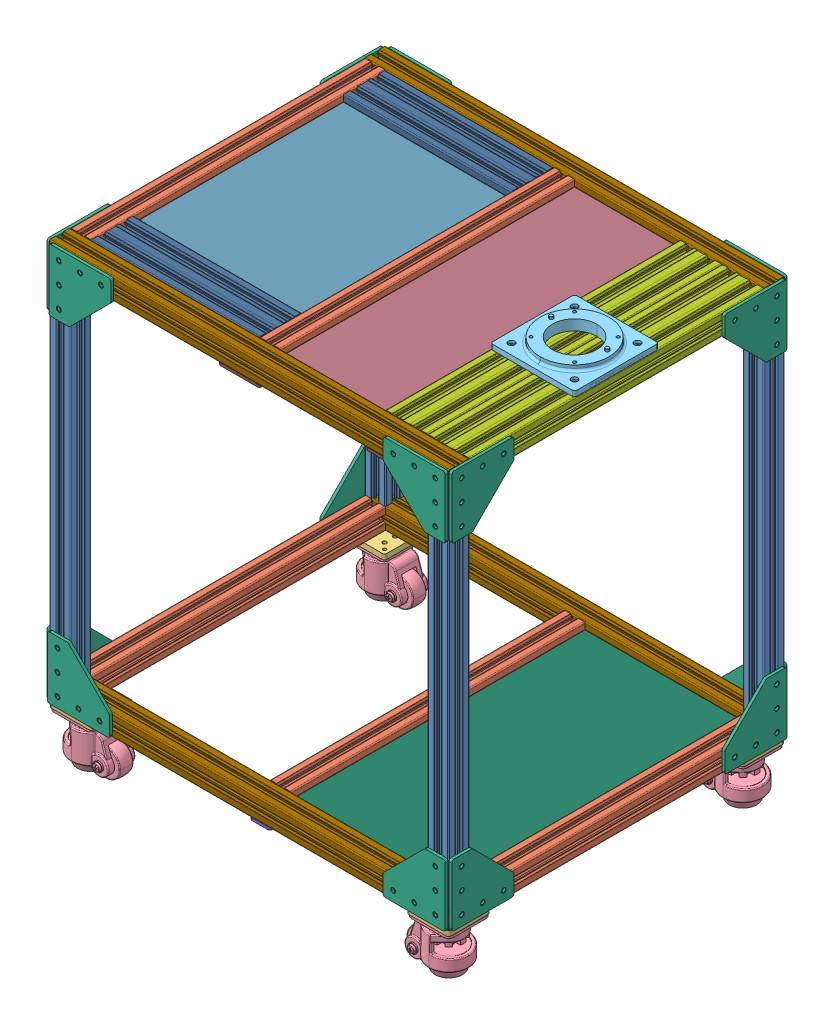
SolidWorks assembly VentionAssembly_13996_v2.7, configuration Default. Lengths in mm.
Overall size (881.9 998.23 752.82).
54 component instances, 15 part files, 4 mates.
Components (placement in the parent):
- VentionAssembly_13996_v2.7.STEP-1: VentionAssembly_13996_v2.7.STEP [Default] at origin size (881.9 998.23 752.82)
  - ST-EXT-001-0765.STEP-1: ST-EXT-001-0765.STEP [Default] at (-347.2932 -765 -630.5247) x (-1 0 0) z (0 1 0) size (45 45 765)
  - ST-EXT-001-0765.STEP-2: ST-EXT-001-0765.STEP [Default] at (-1157.2932 0 -630.5247) x (0 0 -1) z (0 -1 0) size (45 45 765)
  - ST-EXT-001-0765.STEP-3: ST-EXT-001-0765.STEP [Default] at (-1157.2932 0 44.4753) x (0 0 -1) z (0 -1 0) size (45 45 765)
  - ST-EXT-001-0630.STEP-1: ST-EXT-001-0630.STEP [Default] at (-1157.2932 -787.5 21.9753) x (0 -1 0) z (0 0 -1) size (45 45 630)
  - ST-SP-010-0002.STEP-1: ST-SP-010-0002.STEP [Default] at (-1134.7932 -821.25 21.9753) x (0 0 -1) z (1 0 0) size (90 11.25 90)
  - ST-SP-010-0002.STEP-2: ST-SP-010-0002.STEP [Default] at (-1136.7932 -821.25 -608.0247) x (0 0 -1) z (1 0 0) size (90 11.25 90)
  - ST-SP-010-0002.STEP-3: ST-SP-010-0002.STEP [Default] at (-369.7932 -821.25 21.9753) x (0 0 1) z (-1 0 0) size (90 11.25 90)
  - ST-SP-010-0002.STEP-4: ST-SP-010-0002.STEP [Default] at (-369.7932 -821.25 -608.0247) x (0 0 1) z (-1 0 0) size (90 11.25 90)
  - MO-WL-003-0002.STEP-1: MO-WL-003-0002.STEP [Default] at (-1089.2932 -821.25 21.9753) x (0 0 -1) z (1 0 0) size (106.41 104.48 134.91)
  - MO-WL-003-0002.STEP-2: MO-WL-003-0002.STEP [Default] at (-415.2932 -821.25 21.9753) x (0 0 1) z (-1 0 0) size (106.41 104.48 134.91)
  - MO-WL-003-0002.STEP-3: MO-WL-003-0002.STEP [Default] at (-1091.2932 -821.25 -608.0247) x (0 0 -1) z (1 0 0) size (106.41 104.48 134.91)
  - MO-WL-003-0002.STEP-4: MO-WL-003-0002.STEP [Default] at (-415.2932 -821.25 -608.0247) x (0 0 1) z (-1 0 0) size (106.41 104.48 134.91)
  - ST-RB-001-0002.STEP-1: ST-RB-001-0002.STEP [Default] at (-414.7932 45 -293.0247) x (-1 0 0) z (0 0 -1) size (180 27.5 180)
  - ST-EXT-001-0630.STEP-2: ST-EXT-001-0630.STEP [Default] at (-347.2932 -787.5 -608.0247) x (0 -1 0) z (0 0 1) size (45 45 630)
  - ST-GP-001-0009.STEP-1: ST-GP-001-0009.STEP [Default] at (-325.7932 44 72.9753) x (1 0 0) z (0 0 -1) size (133 133 6)
  - ST-GP-001-0009.STEP-2: ST-GP-001-0009.STEP [Default] at (-325.7932 44 -653.0247) x (1 0 0) z (0 0 -1) size (133 133 6)
  - ST-EXT-001-0765.STEP-4: ST-EXT-001-0765.STEP [Default] at (-347.2932 -765 44.4753) x (-1 0 0) z (0 1 0) size (45 45 765)
  - ST-GP-001-0009.STEP-3: ST-GP-001-0009.STEP [Default] at (-324.7932 44 65.9753) x (0 0 1) z (1 0 0) size (133 133 6)
  - ST-GP-001-0009.STEP-4: ST-GP-001-0009.STEP [Default] at (-324.7932 44 -652.0247) x (0 1 0) z (1 0 0) size (133 133 6)
  - ST-EXT-002-0630.STEP-1: ST-EXT-002-0630.STEP [Default] at (-392.2932 22.5 -608.0247) x (-1 0 0) z (0 0 1) size (90 45 630)
  - ST-EXT-002-0630.STEP-2: ST-EXT-002-0630.STEP [Default] at (-482.2932 22.5 -608.0247) x (-1 0 0) z (0 0 1) size (90 45 630)
  - ST-GP-001-0009.STEP-5: ST-GP-001-0009.STEP [Default] at (-325.7932 -809 72.9753) x (0 -1 0) z (0 0 -1) size (133 133 6)
  - ST-GP-001-0009.STEP-6: ST-GP-001-0009.STEP [Default] at (-324.7932 -809 65.9753) x (0 -1 0) z (1 0 0) size (133 133 6)
  - ST-GP-001-0009.STEP-7: ST-GP-001-0009.STEP [Default] at (-324.7932 -809 -652.0247) x (0 0 -1) z (1 0 0) size (133 133 6)
  - ST-GP-001-0009.STEP-8: ST-GP-001-0009.STEP [Default] at (-325.7932 -809 -653.0247) x (0 -1 0) z (0 0 -1) size (133 133 6)
  - ST-EXT-001-0630.STEP-3: ST-EXT-001-0630.STEP [Default] at (-729.7932 -787.5 21.9753) x (0 1 0) z (0 0 -1) size (45 45 630)
  - ST-GP-001-0007.STEP-1: ST-GP-001-0007.STEP [Default] at (-729.7932 -810 -652.0247) x (0 0 1) z (0 -1 0) size (133 43 6)
  - ST-GP-001-0007.STEP-2: ST-GP-001-0007.STEP [Default] at (-729.7932 -810 65.9753) x (0 0 -1) z (0 -1 0) size (133 43 6)
  - ST-EXT-001-0855.STEP-1: ST-EXT-001-0855.STEP [Default] at (-324.7932 22.5 -630.5247) x (0 0 -1) z (-1 0 0) size (45 45 855)
  - ST-EXT-001-0855.STEP-2: ST-EXT-001-0855.STEP [Default] at (-324.7932 22.5 44.4753) x (0 0 -1) z (-1 0 0) size (45 45 855)
  - ST-EXT-001-0855.STEP-3: ST-EXT-001-0855.STEP [Default] at (-324.7932 -787.5 -630.5247) x (0 0 1) z (-1 0 0) size (45 45 855)
  - ST-EXT-001-0855.STEP-4: ST-EXT-001-0855.STEP [Default] at (-324.7932 -787.5 44.4753) x (0 0 1) z (-1 0 0) size (45 45 855)
  - ST-GP-001-0009.STEP-9: ST-GP-001-0009.STEP [Default] at (-1178.7932 -809 -659.0247) x (0 -1 0) z (0 0 1) size (133 133 6)
  - ST-GP-001-0009.STEP-10: ST-GP-001-0009.STEP [Default] at (-1179.7932 -809 -652.0247) x (0 -1 0) z (-1 0 0) size (133 133 6)
  - ST-GP-001-0009.STEP-11: ST-GP-001-0009.STEP [Default] at (-1179.7932 -809 65.9753) x (0 0 1) z (-1 0 0) size (133 133 6)
  - ST-GP-001-0009.STEP-12: ST-GP-001-0009.STEP [Default] at (-1177.7932 -809 66.9753) x (0 -1 0) z (0 0 1) size (133 133 6)
  - ST-GP-001-0009.STEP-13: ST-GP-001-0009.STEP [Default] at (-1174.7932 44 72.9753) x (0 1 0) z (0 0 -1) size (133 133 6)
  - ST-GP-001-0009.STEP-14: ST-GP-001-0009.STEP [Default] at (-1179.7932 44 65.9753) x (0 1 0) z (-1 0 0) size (133 133 6)
  - ST-GP-001-0009.STEP-15: ST-GP-001-0009.STEP [Default] at (-1179.7932 44 -652.0247) x (0 0 -1) z (-1 0 0) size (133 133 6)
  - ST-GP-001-0009.STEP-16: ST-GP-001-0009.STEP [Default] at (-1176.7932 44 -653.0247) x (0 1 0) z (0 0 -1) size (133 133 6)
  - ST-EXT-002-0360.STEP-1: ST-EXT-002-0360.STEP [Default] at (-774.7932 22.5 -585.5247) x (0 0 -1) z (-1 0 0) size (90 45 360)
  - ST-EXT-001-0630.STEP-4: ST-EXT-001-0630.STEP [Default] at (-1157.2932 22.5 -608.0247) x (0 1 0) z (0 0 1) size (45 45 630)
  - ST-EXT-002-0360.STEP-2: ST-EXT-002-0360.STEP [Default] at (-774.7932 22.5 -0.5247) x (0 0 1) z (-1 0 0) size (90 45 360)
  - ST-GP-001-0008.STEP-1: ST-GP-001-0008.STEP [Default] at (-503.7932 0 -22.0247) x (1 0 0) z (0 -1 0) size (133 88 6)
  - ST-EXT-001-0630.STEP-5: ST-EXT-001-0630.STEP [Default] at (-752.2932 22.5 -608.0247) x (0 1 0) z (0 0 1) size (45 45 630)
  - ST-GP-001-0008.STEP-2: ST-GP-001-0008.STEP [Default] at (-370.7932 0 -564.0247) x (-1 0 0) z (0 -1 0) size (133 88 6)
  - ST-GP-001-0008.STEP-3: ST-GP-001-0008.STEP [Default] at (-730.7932 0 -652.0247) x (0 0 1) z (0 -1 0) size (133 88 6)
  - ST-GP-001-0008.STEP-4: ST-GP-001-0008.STEP [Default] at (-730.7932 0 -67.0247) x (0 0 1) z (0 -1 0) size (133 88 6)
  - ST-GP-001-0003.STEP-1: ST-GP-001-0003.STEP [Default] at (-1134.7932 0 -563.0247) x (1 0 0) z (0 -1 0) size (88 88 6)
  - ST-GP-001-0003.STEP-2: ST-GP-001-0003.STEP [Default] at (-1134.7932 0 -23.0247) x (1 0 0) z (0 -1 0) size (88 88 6)
- Large Acrylic Panel - Top^VentionAssembly_13996_v2.7-1: Large Acrylic Panel - Top^VentionAssembly_13996_v2.7 [Default] at origin size (261.03 8 659.72) (virtual)
- Small Acrylic Panel - Top^VentionAssembly_13996_v2.7-1: Small Acrylic Panel - Top^VentionAssembly_13996_v2.7 [Default] at origin size (384.75 8 487.14) (virtual)
- Acrylic Panel - Bottom^VentionAssembly_13996_v2.7-1: Acrylic Panel - Bottom^VentionAssembly_13996_v2.7 [Default] at (-347.2932 -791.5 -608.0247) x (0 0 1) z (0 1 0) size (656.62 377.3 8) (virtual)
Mates (geometry in assembly coordinates):
- InPlace1: in place: plane of VentionAssembly_13996_v2.7.STEP-1/ST-EXT-001-0630.STEP-2 through (-363.3932 -791.5 -518.0247) normal (0 1 0); plane of ? through (0 -791.5 0) normal (0 1 0); moOrthogonalPlaneRef_w of VentionAssembly_13996_v2.7.STEP-1/ST-EXT-001-0630.STEP-2 through (-363.3932 -791.5 -518.0247) normal (0 1 0); plane of ? through (0 -791.5 0) normal (0 0 -1); plane of VentionAssembly_13996_v2.7.STEP-1/ST-EXT-001-0630.STEP-2 through (-363.3932 -791.5 -518.0247) normal (0 1 0); plane of ? through (0 -791.5 0) normal (1 0 0); plane of VentionAssembly_13996_v2.7.STEP-1/ST-EXT-001-0630.STEP-2 through (-363.3932 -791.5 -518.0247) normal (0 1 0); unknown of Acrylic Panel - Bottom^VentionAssembly_13996_v2.7-1
- Coincident1: coincident aligned: plane of VentionAssembly_13996_v2.7.STEP-1/ST-EXT-001-0630.STEP-2; plane of Acrylic Panel - Bottom^VentionAssembly_13996_v2.7-1
- Coincident2: coincident aligned: moOrthogonalPlaneRef_w of VentionAssembly_13996_v2.7.STEP-1/ST-EXT-001-0630.STEP-2 through (-347.2932 -791.5 -608.0247) normal (1 0 0); plane of Acrylic Panel - Bottom^VentionAssembly_13996_v2.7-1 through (-347.2932 -791.5 -608.0247) normal (1 0 0)
- Coincident3: coincident anti-aligned: moOrthogonalPlaneRef_w of VentionAssembly_13996_v2.7.STEP-1/ST-EXT-001-0630.STEP-2 through (-347.2932 -791.5 -608.0247) normal (0 0 -1); plane of Acrylic Panel - Bottom^VentionAssembly_13996_v2.7-1 through (-347.2932 -791.5 -608.0247) normal (0 0 1)
